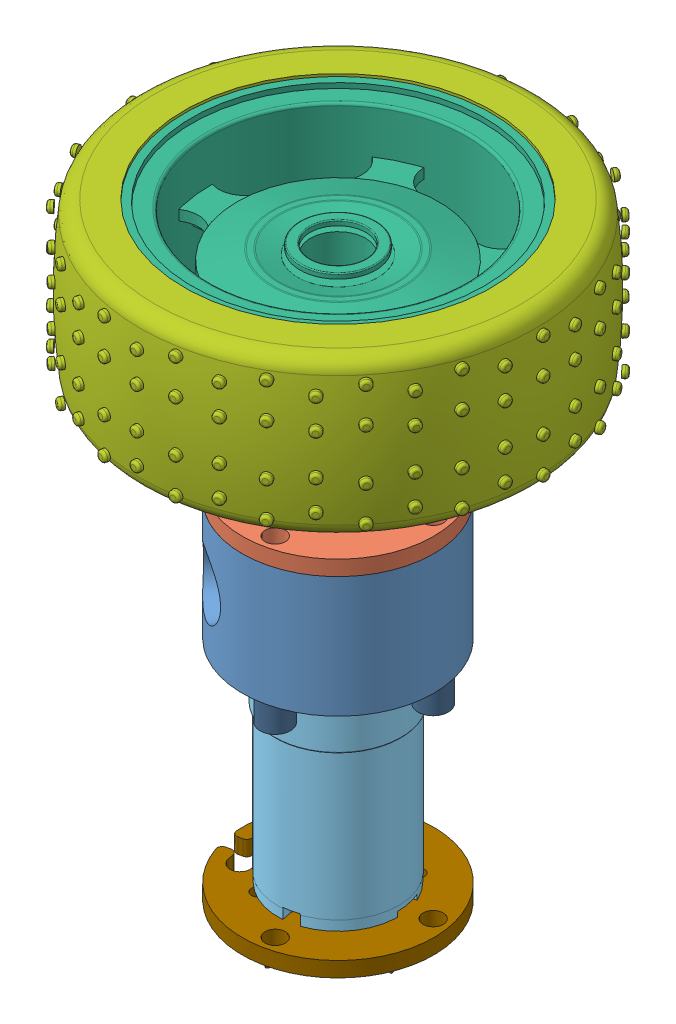
SolidWorks assembly motor_mount, configuration Default. Lengths in mm.
Overall size (127.07 129.29 127.07).
58 component instances, 22 part files, 32 mates.
Components (placement in the parent):
- hjulophæng_p1-1: hjulophæng_p1 [Default] at (31.8914 7.6056 26.5411) x (0.834624 0 0.550821) z (-0.550821 0 0.834624) size (38 24 38)
- hjulophæng_p3-1: hjulophæng_p3 [Default] at (31.8914 31.6056 26.5411) x (0.799939 0 0.600082) z (-0.600082 0 0.799939) size (38 3 38)
- bearing-1: bearing [Default] at (31.8914 23.6056 26.5411) x (0.923181 0 0.384366) z (0 1 0) size (26 26 8.01)
  - bearing-1: bearing [Default] at (0 0 8) x (0 0 -1) z (0 1 0) size (8.01 26 26)
- WheelMount_p2-1: WheelMount_p2 [Default] at (31.8914 23.6056 26.5411) x (0.83699 0 0.547218) z (0 -1 0) size (11 11 41)
- Motor-1: Motor [Default] at (31.8914 15.6056 26.5411) x (0 1 0) z (-0.979657 0 0.200679) size (65.5 25 25)
- tire-1: tire [Default] at (31.6127 70.7597 25.6543) x (-0.299761 0 -0.954014) z (0.954014 0 -0.299761) size (115.91 31.01 115.91)
  - tire_rim-1: tire_rim [Default] at (-0.9296 -18.1541 0) size (61 30 61)
  - tire_rubber-1: tire_rubber [Default] at (-0.9296 -3.1541 0) x (0 -1 0) z (0.683949 0 0.729529) size (31.01 82 82)
- wheel_adaptor-1: wheel_adaptor [Default] at (31.8914 61.6056 26.5411) x (-0.547218 0 0.83699) z (0 -1 0) size (17 17 28)
- encoder_mount-1: encoder_mount [Default] at (31.8914 -34.3944 26.5411) x (0.703895 0 -0.710304) z (0 -1 0) size (38 38 3)
- spacer_m4_5mm-1: spacer_m4_5mm [Default] at (35.1023 2.6056 42.2156) size (6 5 6)
- spacer_m4_5mm-2: spacer_m4_5mm [Default] at (47.5659 2.6056 23.3303) x (0.982082 0 -0.188455) z (0.188455 0 0.982082) size (6 5 6)
- spacer_m4_5mm-6: spacer_m4_5mm [Default] at (28.6805 2.6056 10.8666) x (0.8 0 -0.6) z (0.6 0 0.8) size (6 5 6)
- pcb_encoder-1: pcb_encoder [Default] at (31.9397 -40.3604 26.5232) x (-0.205448 0 -0.978668) z (0 -1 0) size (26.72 26.87 7.85)
  - Dip_encoder-1: Dip_encoder [Default] at origin size (26.72 26.87 0.33)
  - Capacitor 0603_encoder-1: Capacitor 0603_encoder [Default] at (-4.7345 1.7721 0.352) x (0 -1 0) z (-1 0 0) size (1.6 0.86 0.86)
  - Capacitor 0603_encoder-2: Capacitor 0603_encoder [Default] at (1.8045 -7.3354 0.352) x (0 -1 0) z (-1 0 0) size (1.6 0.86 0.86)
  - Capacitor 0805_encoder-1: Capacitor 0805_encoder [Default] at (4.0892 5.0823 0.352) x (0 1 0) z (1 0 0) size (2 0.76 1.31)
  - Capacitor 0805_encoder-2: Capacitor 0805_encoder [Default] at (0.293 -10.3648 0.352) x (-1 0 0) z (0 1 0) size (2 0.76 1.31)
  - Hole_Hole_encoder-1: Hole_Hole_encoder [Default] at (6.032 -6.032 0.322)
  - Hole_Hole_encoder-2: Hole_Hole_encoder [Default] at (-6.032 6.032 0.322)
  - ISP_Header_encoder-1: ISP_Header_encoder [Default] at (2.2632 8.433 0.322) x (-1 0 0) z (0 1 0) size (3.81 7.85 3.4)
  - res0402-1_encoder-1: res0402-1_encoder [По умолчанию] at (3.8945 9.9406 0.335) x (0 1 0) z (0 0 1) size (1 0.5 0.3)
  - res0402-1_encoder-2: res0402-1_encoder [По умолчанию] at (0.838 -3.465 0.322) size (1 0.5 0.3)
  - res0402-1_encoder-3: res0402-1_encoder [По умолчанию] at (2.515 -1.945 0.322) size (1 0.5 0.3)
  - res0402-1_encoder-4: res0402-1_encoder [По умолчанию] at (0.457 -10.099 0) x (-1 0 0) z (0 0 -1) size (1 0.5 0.3)
  - res0402-1_encoder-5: res0402-1_encoder [По умолчанию] at (0.457 -9.184 0) x (-1 0 0) z (0 0 -1) size (1 0.5 0.3)
  - Static_Via_Static_Via_encoder-1: Static_Via_Static_Via_encoder [Default] at (-7.62 2.54 0.322)
  - Static_Via_Static_Via_encoder-2: Static_Via_Static_Via_encoder [Default] at (-7.62 0 0.322)
  - Static_Via_Static_Via_encoder-3: Static_Via_Static_Via_encoder [Default] at (-10.16 5.08 0.322)
  - Static_Via_Static_Via_encoder-4: Static_Via_Static_Via_encoder [Default] at (7.62 -2.54 0.322)
  - Static_Via_Static_Via_encoder-5: Static_Via_Static_Via_encoder [Default] at (5.08 7.62 0.322)
  - Static_Via_Static_Via_encoder-6: Static_Via_Static_Via_encoder [Default] at (10.16 2.54 0.322)
  - Static_Via_Static_Via_encoder-7: Static_Via_Static_Via_encoder [Default] at (10.16 -2.54 0.322)
  - Static_Via_Static_Via_encoder-8: Static_Via_Static_Via_encoder [Default] at (-7.62 -7.62 0.322)
  - Static_Via_Static_Via_encoder-9: Static_Via_Static_Via_encoder [Default] at (-2.54 -10.16 0.322)
  - Static_Via_Static_Via_encoder-10: Static_Via_Static_Via_encoder [Default] at (-5.08 -7.62 0.322)
  - Static_Via_Static_Via_encoder-11: Static_Via_Static_Via_encoder [Default] at (-7.62 -5.08 0.322)
  - Static_Via_Static_Via_encoder-12: Static_Via_Static_Via_encoder [Default] at (-10.16 -2.54 0.322)
  - Static_Via_Static_Via_encoder-13: Static_Via_Static_Via_encoder [Default] at (-10.16 0 0.322)
  - Static_Via_Static_Via_encoder-14: Static_Via_Static_Via_encoder [Default] at (-10.16 2.54 0.322)
  - Static_Via_Static_Via_encoder-15: Static_Via_Static_Via_encoder [Default] at (5.08 -10.16 0.322)
  - Static_Via_Static_Via_encoder-16: Static_Via_Static_Via_encoder [Default] at (7.62 2.54 0.322)
  - Static_Via_Static_Via_encoder-17: Static_Via_Static_Via_encoder [Default] at (7.62 7.62 0.322)
  - Static_Via_Static_Via_encoder-18: Static_Via_Static_Via_encoder [Default] at (10.16 5.08 0.322)
  - Static_Via_Static_Via_encoder-19: Static_Via_Static_Via_encoder [Default] at (10.16 0 0.322)
  - Static_Via_Static_Via_encoder-20: Static_Via_Static_Via_encoder [Default] at (10.16 -5.08 0.322)
  - Static_Via_Static_Via_encoder-21: Static_Via_Static_Via_encoder [Default] at (-5.08 -10.16 0.322)
  - Static_Via_Static_Via_encoder-22: Static_Via_Static_Via_encoder [Default] at (-10.16 -5.08 0.322)
  - Static_Via_Static_Via_encoder-23: Static_Via_Static_Via_encoder [Default] at (-5.08 10.16 0.322)
  - Static_Via_Static_Via_encoder-24: Static_Via_Static_Via_encoder [Default] at (-2.54 10.16 0.322)
  - S4B-ZR-SM4A-TF_encoder-1: S4B-ZR-SM4A-TF_encoder [Default] at (-3.7914 -3.8279 0.322) x (0.707107 -0.707107 0) z (-0.707107 -0.707107 0) size (9 3.7 6.5)
  - tssop14-2_encoder-1: tssop14-2_encoder [По умолчанию] at (-0.0271 0.0569 0) x (0 1 0) z (0 0 -1) size (6.4 5.1 1.2)
  - ATmega 168_encoder-1: ATmega 168_encoder [Default] at (-0.724 0.144 0.322) x (1 0 0) z (0 -1 0) size (4 0.82 4)
  - GeyerElectronics_KX14_encoder-1: GeyerElectronics_KX14_encoder [По умолчанию] at (7.493 2.515 0) x (0 -1 0) z (1 0 0) size (8 1.62 4.5)
- spacer_m3_3mm-1: spacer_m3_3mm [Default] at (24.7971 -40.3944 21.8592) size (7 3 7)
- spacer_m3_3mm-2: spacer_m3_3mm [Default] at (38.9857 -40.3944 31.2231) x (0.982082 0 -0.188455) z (0.188455 0 0.982082) size (7 3 7)
Mates (geometry in assembly coordinates):
- Concentric1: concentric anti-aligned: cylinder of hjulophæng_p1-1 through (31.8914 23.6056 26.5411) axis (0 1 0) radius 13; cylinder of bearing-1/bearing-1 through (31.8914 27.6056 26.5411) axis (0 -1 0) radius 13
- Coincident1: coincident anti-aligned: plane of hjulophæng_p1-1 through (31.8914 23.6056 26.5411) normal (0 1 0); plane of bearing-1/bearing-1 through (20.854 23.6056 21.9457) normal (0 -1 0)
- Concentric2: concentric aligned: cylinder of hjulophæng_p1-1 through (47.5659 7.6056 23.3303) axis (0 1 0) radius 1.5; cylinder of hjulophæng_p3-1 through (47.5659 31.6056 23.3303) axis (0 1 0) radius 2
- Concentric3: concentric aligned: cylinder of hjulophæng_p1-1 through (16.2169 7.6056 29.752) axis (0 1 0) radius 1.5; cylinder of hjulophæng_p3-1 through (16.2169 31.6056 29.752) axis (0 1 0) radius 2
- Coincident2: coincident anti-aligned: plane of hjulophæng_p1-1 through (31.8914 31.6056 26.5411) normal (0 1 0); plane of hjulophæng_p3-1 through (31.8914 31.6056 26.5411) normal (0 -1 0)
- Concentric4: concentric aligned: cylinder of bearing-1/bearing-1 through (31.8914 27.6056 26.5411) axis (0 -1 0) radius 5; cylinder of WheelMount_p2-1 through (31.8914 56.6056 26.5411) axis (0 -1 0) radius 5
- Coincident3: coincident anti-aligned: plane of bearing-1/bearing-1 through (26.0717 23.6056 24.1181) normal (0 -1 0); plane of WheelMount_p2-1 through (36.4948 23.6056 29.5508) normal (0 1 0)
- Concentric5: concentric aligned: cylinder of hjulophæng_p1-1 through (30.1856 7.6056 18.2141) axis (0 1 0) radius 1.5; cylinder of Motor-1 through (30.1856 13.6056 18.2141) axis (0 1 0) radius 0.7835
- Concentric6: concentric aligned: cylinder of hjulophæng_p1-1 through (33.5972 7.6056 34.8682) axis (0 1 0) radius 1.5; cylinder of Motor-1 through (33.5972 13.6056 34.8682) axis (0 1 0) radius 0.7835
- Coincident4: coincident anti-aligned: plane of hjulophæng_p1-1 through (31.8914 15.6056 26.5411) normal (0 -1 0); plane of Motor-1 through (31.8914 15.6056 26.5411) normal (0 1 0)
- Concentric10: concentric anti-aligned: cylinder of WheelMount_p2-1 through (31.8914 56.6056 26.5411) axis (0 -1 0) radius 5; cylinder of wheel_adaptor-1 through (31.8914 36.6056 26.5411) axis (0 1 0) radius 5
- Concentric11: concentric aligned: cylinder of WheelMount_p2-1 through (31.8914 43.6056 26.5411) axis (-0.547218 0 0.83699) radius 2; cylinder of wheel_adaptor-1 through (36.5433 43.6056 19.4259) axis (-0.547218 0 0.83699) radius 2
- Concentric16: concentric aligned: cylinder of tire-1/tire_rim-1 through (31.8914 -24.7289 26.5411) axis (0 1 0) radius 2; cylinder of wheel_adaptor-1 through (31.8914 56.6056 26.5411) axis (0 1 0) radius 2
- Parallel3: parallel anti-aligned: plane of tire-1/tire_rim-1 through (36.9409 61.6056 21.6932) normal (-0.278435 0 0.960455); plane of wheel_adaptor-1 through (35.2232 64.6056 23.3423) normal (0.278435 0 -0.960455)
- Coincident7: coincident anti-aligned: plane of tire-1/tire_rim-1 through (31.8914 64.6056 26.5411) normal (0 -1 0); plane of wheel_adaptor-1 through (31.8914 64.6056 26.5411) normal (0 1 0)
- Concentric17: concentric anti-aligned: cylinder of hjulophæng_p1-1 through (35.1023 7.6056 42.2156) axis (0 1 0) radius 1.5; cylinder of spacer_m4_5mm-1 through (35.1023 7.6056 42.2156) axis (0 -1 0) radius 2
- Coincident8: coincident anti-aligned: plane of hjulophæng_p1-1 through (31.8914 7.6056 26.5411) normal (0 -1 0); plane of spacer_m4_5mm-1 through (35.1023 7.6056 42.2156) normal (0 1 0)
- Concentric18: concentric anti-aligned: cylinder of hjulophæng_p1-1 through (47.5659 7.6056 23.3303) axis (0 1 0) radius 1.5; cylinder of spacer_m4_5mm-2 through (47.5659 7.6056 23.3303) axis (0 -1 0) radius 2
- Coincident9: coincident anti-aligned: plane of hjulophæng_p1-1 through (31.8914 7.6056 26.5411) normal (0 -1 0); plane of spacer_m4_5mm-2 through (47.5659 7.6056 23.3303) normal (0 1 0)
- Concentric20: concentric anti-aligned: cylinder of hjulophæng_p1-1 through (28.6805 7.6056 10.8666) axis (0 1 0) radius 1.5; cylinder of spacer_m4_5mm-6 through (28.6805 7.6056 10.8666) axis (0 -1 0) radius 2
- Coincident11: coincident anti-aligned: plane of hjulophæng_p1-1 through (31.8914 7.6056 26.5411) normal (0 -1 0); plane of spacer_m4_5mm-6 through (28.6805 7.6056 10.8666) normal (0 1 0)
- Concentric22: concentric anti-aligned: cylinder of encoder_mount-1 through (35.1023 -37.3944 42.2156) axis (0 1 0) radius 2; cylinder of spacer_m4_5mm-1 through (35.1023 7.6056 42.2156) axis (0 -1 0) radius 2
- Concentric23: concentric anti-aligned: cylinder of encoder_mount-1 through (28.6805 -37.3944 10.8666) axis (0 1 0) radius 2; cylinder of spacer_m4_5mm-6 through (28.6805 7.6056 10.8666) axis (0 -1 0) radius 2
- Concentric24: concentric anti-aligned: cylinder of encoder_mount-1 through (47.5659 -37.3944 23.3303) axis (0 1 0) radius 2; cylinder of spacer_m4_5mm-2 through (47.5659 7.6056 23.3303) axis (0 -1 0) radius 2
- Coincident12: coincident anti-aligned: plane of Motor-1 through (31.8914 -34.3944 26.5411) normal (0 -1 0); plane of encoder_mount-1 through (18.9287 -34.3944 33.0244) normal (0 1 0)
- Concentric25: concentric anti-aligned: cylinder of encoder_mount-1 through (24.7971 -37.3944 21.8592) axis (0 1 0) radius 1.5; cylinder of spacer_m3_3mm-1 through (24.7971 -37.3944 21.8592) axis (0 -1 0) radius 1.5
- Coincident13: coincident anti-aligned: plane of encoder_mount-1 through (18.9287 -37.3944 33.0244) normal (0 -1 0); plane of spacer_m3_3mm-1 through (24.7971 -37.3944 21.8592) normal (0 1 0)
- Concentric26: concentric anti-aligned: cylinder of encoder_mount-1 through (38.9857 -37.3944 31.2231) axis (0 1 0) radius 1.5; cylinder of spacer_m3_3mm-2 through (38.9857 -37.3944 31.2231) axis (0 -1 0) radius 1.5
- Coincident14: coincident anti-aligned: plane of encoder_mount-1 through (18.9287 -37.3944 33.0244) normal (0 -1 0); plane of spacer_m3_3mm-2 through (38.9857 -37.3944 31.2231) normal (0 1 0)
- Concentric27: concentric anti-aligned: cylinder of pcb_encoder-1/Dip_encoder-1 through (24.7971 -40.6484 21.8592) axis (0 1 0) radius 1.397; cylinder of spacer_m3_3mm-1 through (24.7971 -37.3944 21.8592) axis (0 -1 0) radius 1.5
- Coincident15: coincident anti-aligned: plane of pcb_encoder-1/Dip_encoder-1 through (31.9548 -40.3944 26.5001) normal (0 1 0); plane of spacer_m3_3mm-1 through (24.7971 -40.3944 21.8592) normal (0 -1 0)
- Tangent2: tangent: circle of pcb_encoder-1/Dip_encoder-1; circle of spacer_m3_3mm-2
